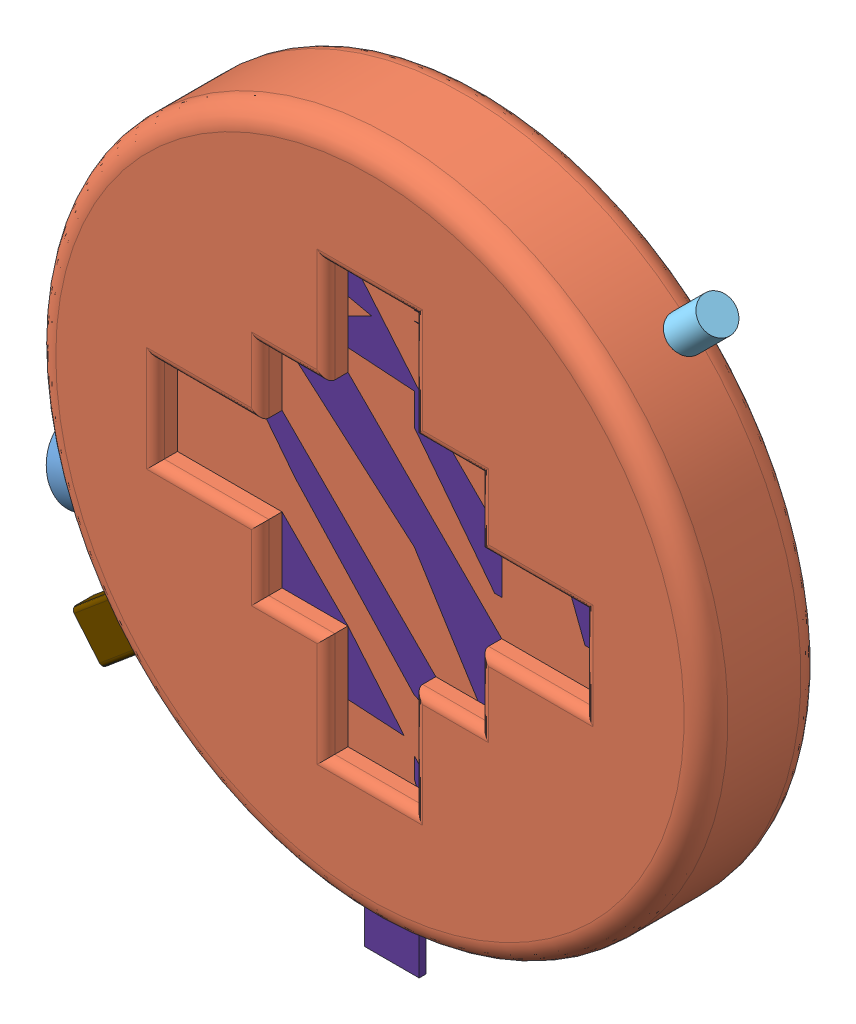
SolidWorks assembly Semafor_s_obalem, configuration Výchozí. Lengths in mm.
Overall size (155.23 162.78 26.6).
173 component instances, 20 part files, 3 mates.
Components (placement in the parent):
- Semafor_kompletni-1: Semafor_kompletni [Výchozí] at origin size (153.13 160.68 23.55)
  - Semafor-1: Semafor [Výchozí] at origin size (148.79 160.68 22.8)
    - Semafor.step-1: Semafor.step [Výchozí] at origin size (148.79 160.68 22.8)
      - LED_WS2812B_PLCC4_5.0x5.0mm_P3.2mm.step-1: LED_WS2812B_PLCC4_5.0x5.0mm_P3.2mm.step [Výchozí] at (-39.4282 65.1 1.65) x (0.5 0.866025 0) z (0 0 1) size (5.4 5 1.6)
        - SOLID.step-1: SOLID.step [Výchozí] at origin size (5.4 5 1.6)
      - LED_WS2812B_PLCC4_5.0x5.0mm_P3.2mm.step-2: LED_WS2812B_PLCC4_5.0x5.0mm_P3.2mm.step [Výchozí] at (-30.05 100.1 1.65) x (0 1 0) z (0 0 1) size (5.4 5 1.6)
        - SOLID.step-1: SOLID.step [Výchozí] at origin size (5.4 5 1.6)
      - LED_WS2812B_PLCC4_5.0x5.0mm_P3.2mm.step-3: LED_WS2812B_PLCC4_5.0x5.0mm_P3.2mm.step [Výchozí] at (-170.05 100.1 1.65) x (0 -1 0) z (0 0 1) size (5.4 5 1.6)
        - SOLID.step-1: SOLID.step [Výchozí] at origin size (5.4 5 1.6)
      - C_0603_1608Metric.step-1: C_0603_1608Metric.step [Výchozí] at (-101.75 33.8 1.65) size (1.6 0.8 0.8)
        - SOLID-0.step-1: SOLID-0.step [Výchozí] at origin size (1.6 0.8 0.8)
      - C_0603_1608Metric.step-2: C_0603_1608Metric.step [Výchozí] at (-43.5875 65.6288 1.65) x (0.5 0.866025 0) z (0 0 1) size (1.6 0.8 0.8)
        - SOLID-0.step-1: SOLID-0.step [Výchozí] at origin size (1.6 0.8 0.8)
      - C_0603_1608Metric.step-3: C_0603_1608Metric.step [Výchozí] at (-134.4288 43.6125 1.65) x (0.866025 -0.5 0) z (0 0 1) size (1.6 0.8 0.8)
        - SOLID-0.step-1: SOLID-0.step [Výchozí] at origin size (1.6 0.8 0.8)
      - C_0603_1608Metric.step-4: C_0603_1608Metric.step [Výchozí] at (-166.15 101.75 1.65) x (0 -1 0) z (0 0 1) size (1.6 0.8 0.8)
        - SOLID-0.step-1: SOLID-0.step [Výchozí] at origin size (1.6 0.8 0.8)
      - LED_WS2812B_PLCC4_5.0x5.0mm_P3.2mm.step-4: LED_WS2812B_PLCC4_5.0x5.0mm_P3.2mm.step [Výchozí] at (-100.05 30.1 1.65) size (5.4 5 1.6)
        - SOLID.step-1: SOLID.step [Výchozí] at origin size (5.4 5 1.6)
      - C_0603_1608Metric.step-5: C_0603_1608Metric.step [Výchozí] at (-158.05 68.5 1.65) x (0.5 -0.866025 0) z (0 0 1) size (1.6 0.8 0.8)
        - SOLID-0.step-1: SOLID-0.step [Výchozí] at origin size (1.6 0.8 0.8)
      - C_0603_1608Metric.step-6: C_0603_1608Metric.step [Výchozí] at (-68.35 41.95 1.65) x (0.866025 0.5 0) z (0 0 1) size (1.6 0.8 0.8)
        - SOLID-0.step-1: SOLID-0.step [Výchozí] at origin size (1.6 0.8 0.8)
      - LED_WS2812B_PLCC4_5.0x5.0mm_P3.2mm.step-5: LED_WS2812B_PLCC4_5.0x5.0mm_P3.2mm.step [Výchozí] at (-100.05 170.1 1.65) x (-1 0 0) z (0 0 1) size (5.4 5 1.6)
        - SOLID.step-1: SOLID.step [Výchozí] at origin size (5.4 5 1.6)
      - LED_WS2812B_PLCC4_5.0x5.0mm_P3.2mm.step-6: LED_WS2812B_PLCC4_5.0x5.0mm_P3.2mm.step [Výchozí] at (-39.4282 135.1 1.65) x (-0.5 0.866025 0) z (0 0 1) size (5.4 5 1.6)
        - SOLID.step-1: SOLID.step [Výchozí] at origin size (5.4 5 1.6)
      - LED_WS2812B_PLCC4_5.0x5.0mm_P3.2mm.step-7: LED_WS2812B_PLCC4_5.0x5.0mm_P3.2mm.step [Výchozí] at (-160.6718 65.1 1.65) x (0.5 -0.866025 0) z (0 0 1) size (5.4 5 1.6)
        - SOLID.step-1: SOLID.step [Výchozí] at origin size (5.4 5 1.6)
      - LED_WS2812B_PLCC4_5.0x5.0mm_P3.2mm.step-8: LED_WS2812B_PLCC4_5.0x5.0mm_P3.2mm.step [Výchozí] at (-65.05 39.4782 1.65) x (0.866025 0.5 0) z (0 0 1) size (5.4 5 1.6)
        - SOLID.step-1: SOLID.step [Výchozí] at origin size (5.4 5 1.6)
      - C_0603_1608Metric.step-7: C_0603_1608Metric.step [Výchozí] at (-65.45 156.55 1.65) x (-0.866025 0.5 0) z (0 0 1) size (1.6 0.8 0.8)
        - SOLID-0.step-1: SOLID-0.step [Výchozí] at origin size (1.6 0.8 0.8)
      - C_0603_1608Metric.step-8: C_0603_1608Metric.step [Výchozí] at (-33.9 98.45 1.65) x (0 1 0) z (0 0 1) size (1.6 0.8 0.8)
        - SOLID-0.step-1: SOLID-0.step [Výchozí] at origin size (1.6 0.8 0.8)
      - C_0603_1608Metric.step-9: C_0603_1608Metric.step [Výchozí] at (-98.4 166.3 1.65) x (-1 0 0) z (0 0 1) size (1.6 0.8 0.8)
        - SOLID-0.step-1: SOLID-0.step [Výchozí] at origin size (1.6 0.8 0.8)
      - LED_WS2812B_PLCC4_5.0x5.0mm_P3.2mm.step-9: LED_WS2812B_PLCC4_5.0x5.0mm_P3.2mm.step [Výchozí] at (-160.6718 135.1 1.65) x (-0.5 -0.866025 0) z (0 0 1) size (5.4 5 1.6)
        - SOLID.step-1: SOLID.step [Výchozí] at origin size (5.4 5 1.6)
      - LED_WS2812B_PLCC4_5.0x5.0mm_P3.2mm.step-10: LED_WS2812B_PLCC4_5.0x5.0mm_P3.2mm.step [Výchozí] at (-65.05 160.7218 1.65) x (-0.866025 0.5 0) z (0 0 1) size (5.4 5 1.6)
        - SOLID.step-1: SOLID.step [Výchozí] at origin size (5.4 5 1.6)
      - C_0603_1608Metric.step-10: C_0603_1608Metric.step [Výchozí] at (-156.35 134.6 1.65) x (-0.5 -0.866025 0) z (0 0 1) size (1.6 0.8 0.8)
        - SOLID-0.step-1: SOLID-0.step [Výchozí] at origin size (1.6 0.8 0.8)
      - LED_WS2812B_PLCC4_5.0x5.0mm_P3.2mm.step-11: LED_WS2812B_PLCC4_5.0x5.0mm_P3.2mm.step [Výchozí] at (-135.05 160.7218 1.65) x (-0.866025 -0.5 0) z (0 0 1) size (5.4 5 1.6)
        - SOLID.step-1: SOLID.step [Výchozí] at origin size (5.4 5 1.6)
      - C_0603_1608Metric.step-11: C_0603_1608Metric.step [Výchozí] at (-131.65 158.3 1.65) x (-0.866025 -0.5 0) z (0 0 1) size (1.6 0.8 0.8)
        - SOLID-0.step-1: SOLID-0.step [Výchozí] at origin size (1.6 0.8 0.8)
      - C_0603_1608Metric.step-12: C_0603_1608Metric.step [Výchozí] at (-42.05 131.8 1.65) x (-0.5 0.866025 0) z (0 0 1) size (1.6 0.8 0.8)
        - SOLID-0.step-1: SOLID-0.step [Výchozí] at origin size (1.6 0.8 0.8)
      - LED_WS2812B_PLCC4_5.0x5.0mm_P3.2mm.step-12: LED_WS2812B_PLCC4_5.0x5.0mm_P3.2mm.step [Výchozí] at (-135.05 39.4782 1.65) x (0.866025 -0.5 0) z (0 0 1) size (5.4 5 1.6)
        - SOLID.step-1: SOLID.step [Výchozí] at origin size (5.4 5 1.6)
      - R_0603_1608Metric.step-1: R_0603_1608Metric.step [Výchozí] at (-119.75 147.925 -0.05) x (0 -1 0) z (0 0 -1) size (1.6 0.8 0.45)
        - SOLID-1.step-1: SOLID-1.step [Výchozí] at origin size (1.6 0.8 0.45)
      - R_0603_1608Metric.step-2: R_0603_1608Metric.step [Výchozí] at (-115.95 147.9 -0.05) x (0 -1 0) z (0 0 -1) size (1.6 0.8 0.45)
        - SOLID-1.step-1: SOLID-1.step [Výchozí] at origin size (1.6 0.8 0.45)
      - D_SOD-123.step-1: D_SOD-123.step [Výchozí] at (-130.0125 82.075 -0.05) x (-1 0 0) z (0 0 -1) size (3.8 1.6 1.25)
        - SOLID-2.step-1: SOLID-2.step [Výchozí] at origin size (3.8 1.6 1.25)
      - E22_900T22D.step-1: E22_900T22D.step [Výchozí] at (-60.45 137.7711 -0.05) x (-0.707107 -0.707107 0) z (0 0 -1) size (50 21 17.3)
        - SOLID-3.step-1: SOLID-3.step [Výchozí] at origin size (50 21 17.3)
      - D_SOD-123.step-2: D_SOD-123.step [Výchozí] at (-96.1 29.05 -0.05) x (0 -1 0) z (0 0 -1) size (3.8 1.6 1.25)
        - SOLID-2.step-1: SOLID-2.step [Výchozí] at origin size (3.8 1.6 1.25)
      - PinSocket_1x03_P2.54mm_Vertical.step-1: PinSocket_1x03_P2.54mm_Vertical.step [Výchozí] at (-143.675 75.375 -0.05) x (0 1 0) z (0 0 -1) size (2.54 7.62 10.1)
        - SOLID-4.step-1: SOLID-4.step [Výchozí] at origin size (2.54 7.62 10.1)
      - D_SOD-323.step-1: D_SOD-323.step [Výchozí] at (-142.6 58.8 -0.05) x (0.642788 -0.766044 0) z (0 0 -1) size (2.5 1.25 1.1)
        - SOLID-5.step-1: SOLID-5.step [Výchozí] at origin size (2.5 1.25 1.1)
      - C_0603_1608Metric.step-13: C_0603_1608Metric.step [Výchozí] at (-158.9591 131.0993 -0.05) x (-0.939693 0.34202 0) z (0 0 -1) size (1.6 0.8 0.8)
        - SOLID-0.step-1: SOLID-0.step [Výchozí] at origin size (1.6 0.8 0.8)
      - R_0603_1608Metric.step-3: R_0603_1608Metric.step [Výchozí] at (-83.3756 132.275 -0.05) x (-1 0 0) z (0 0 -1) size (1.6 0.8 0.45)
        - SOLID-1.step-1: SOLID-1.step [Výchozí] at origin size (1.6 0.8 0.45)
      - R_0603_1608Metric.step-4: R_0603_1608Metric.step [Výchozí] at (-118.05 147.9 -0.05) x (0 -1 0) z (0 0 -1) size (1.6 0.8 0.45)
        - SOLID-1.step-1: SOLID-1.step [Výchozí] at origin size (1.6 0.8 0.45)
      - R_0603_1608Metric.step-5: R_0603_1608Metric.step [Výchozí] at (-116.95 136.3 -0.05) x (0 -1 0) z (0 0 -1) size (1.6 0.8 0.45)
        - SOLID-1.step-1: SOLID-1.step [Výchozí] at origin size (1.6 0.8 0.45)
      - C_0805_2012Metric.step-1: C_0805_2012Metric.step [Výchozí] at (-152.9591 126.5493 -0.05) x (0.939693 -0.34202 0) z (0 0 -1) size (2 1.25 1.25)
        - SOLID-6.step-1: SOLID-6.step [Výchozí] at origin size (2 1.25 1.25)
      - LED_0603_1608Metric.step-1: LED_0603_1608Metric.step [Výchozí] at (-147.525 84.025 -0.05) x (-1 0 0) z (0 0 -1) size (1.6 0.8 1.1)
        - SOLID-7.step-1: SOLID-7.step [Výchozí] at origin size (1.6 0.8 1.1)
      - SOT-23.step-1: SOT-23.step [Výchozí] at (-83.3256 136.55 -0.05) x (0 1 0) z (0 0 -1) size (2.5 3 1.2)
        - SOLID-8.step-1: SOLID-8.step [Výchozí] at origin size (2.5 3 1.2)
      - SOT-23.step-2: SOT-23.step [Výchozí] at (-146.9091 122.0993 -0.05) x (0.939693 -0.34202 0) z (0 0 -1) size (2.5 3 1.2)
        - SOLID-8.step-1: SOLID-8.step [Výchozí] at origin size (2.5 3 1.2)
      - R_0603_1608Metric.step-6: R_0603_1608Metric.step [Výchozí] at (-120.725 43.975 -0.05) x (-1 0 0) z (0 0 -1) size (1.6 0.8 0.45)
        - SOLID-1.step-1: SOLID-1.step [Výchozí] at origin size (1.6 0.8 0.45)
      - C_0805_2012Metric.step-2: C_0805_2012Metric.step [Výchozí] at (-159.7591 129.0993 -0.05) x (-0.939693 0.34202 0) z (0 0 -1) size (2 1.25 1.25)
        - SOLID-6.step-1: SOLID-6.step [Výchozí] at origin size (2 1.25 1.25)
      - R_0603_1608Metric.step-7: R_0603_1608Metric.step [Výchozí] at (-120.15 136.3 -0.05) x (0 -1 0) z (0 0 -1) size (1.6 0.8 0.45)
        - SOLID-1.step-1: SOLID-1.step [Výchozí] at origin size (1.6 0.8 0.45)
      - D_SOD-323.step-2: D_SOD-323.step [Výchozí] at (-147.5 62.875 -0.05) x (-0.766044 -0.642788 0) z (0 0 -1) size (2.5 1.25 1.1)
        - SOLID-5.step-1: SOLID-5.step [Výchozí] at origin size (2.5 1.25 1.1)
      - C_0805_2012Metric.step-3: C_0805_2012Metric.step [Výchozí] at (-128.3875 78.75 -0.05) x (0 -1 0) z (0 0 -1) size (2 1.25 1.25)
        - SOLID-6.step-1: SOLID-6.step [Výchozí] at origin size (2 1.25 1.25)
      - R_0603_1608Metric.step-8: R_0603_1608Metric.step [Výchozí] at (-143.0091 117.4493 -0.05) x (0.939693 -0.34202 0) z (0 0 -1) size (1.6 0.8 0.45)
        - SOLID-1.step-1: SOLID-1.step [Výchozí] at origin size (1.6 0.8 0.45)
      - LED_0603_1608Metric.step-2: LED_0603_1608Metric.step [Výchozí] at (-109.425 43.2125 -0.05) x (0 -1 0) z (0 0 -1) size (1.6 0.8 1.1)
        - SOLID-7.step-1: SOLID-7.step [Výchozí] at origin size (1.6 0.8 1.1)
      - R_0603_1608Metric.step-9: R_0603_1608Metric.step [Výchozí] at (-135.1875 77.025 -0.05) x (0 1 0) z (0 0 -1) size (1.6 0.8 0.45)
        - SOLID-1.step-1: SOLID-1.step [Výchozí] at origin size (1.6 0.8 0.45)
      - USB_C.step-1: USB_C.step [Výchozí] at (-154.7 55.1 -0.05) x (-0.766044 -0.642788 0) z (0 0 -1) size (7.5 9 3.5)
        - SOLID-9.step-1: SOLID-9.step [Výchozí] at origin size (7.5 9 3.5)
      - Battery_pack.step-1: Battery_pack.step [Výchozí] at (-99.9 62.1 -0.05) x (-1 0 0) z (0 0 -1) size (77 21 19.5)
        - SOLID-10.step-1: SOLID-10.step [Výchozí] at origin size (77 21 19.5)
      - LED_0603_1608Metric.step-3: LED_0603_1608Metric.step [Výchozí] at (-107.575 43.225 -0.05) x (0 -1 0) z (0 0 -1) size (1.6 0.8 1.1)
        - SOLID-7.step-1: SOLID-7.step [Výchozí] at origin size (1.6 0.8 1.1)
      - R_0603_1608Metric.step-10: R_0603_1608Metric.step [Výchozí] at (-144.1125 87.05 -0.05) x (1 0 0) z (0 0 -1) size (1.6 0.8 0.45)
        - SOLID-1.step-1: SOLID-1.step [Výchozí] at origin size (1.6 0.8 0.45)
      - D_SOD-123.step-3: D_SOD-123.step [Výchozí] at (-117.975 155.17 -0.05) x (-1 0 0) z (0 0 -1) size (3.8 1.6 1.25)
        - SOLID-2.step-1: SOLID-2.step [Výchozí] at origin size (3.8 1.6 1.25)
      - R_0603_1608Metric.step-11: R_0603_1608Metric.step [Výchozí] at (-114.175 160.345 -0.05) x (0 -1 0) z (0 0 -1) size (1.6 0.8 0.45)
        - SOLID-1.step-1: SOLID-1.step [Výchozí] at origin size (1.6 0.8 0.45)
      - R_0603_1608Metric.step-12: R_0603_1608Metric.step [Výchozí] at (-150.9091 118.3743 -0.05) x (-0.34202 -0.939693 0) z (0 0 -1) size (1.6 0.8 0.45)
        - SOLID-1.step-1: SOLID-1.step [Výchozí] at origin size (1.6 0.8 0.45)
      - D_SOD-323.step-3: D_SOD-323.step [Výchozí] at (-98.4 29.65 -0.05) x (0 1 0) z (0 0 -1) size (2.5 1.25 1.1)
        - SOLID-5.step-1: SOLID-5.step [Výchozí] at origin size (2.5 1.25 1.1)
      - SOIC-14_3.9x8.7mm_P1.27mm.step-1: SOIC-14_3.9x8.7mm_P1.27mm.step [Výchozí] at (-118.5 142.1 -0.05) x (0 -1 0) z (0 0 -1) size (6 8.7 1.75)
        - SOLID-11.step-1: SOLID-11.step [Výchozí] at origin size (6 8.7 1.75)
      - C_0603_1608Metric.step-14: C_0603_1608Metric.step [Výchozí] at (-124.55 142.3493 -0.05) x (0 -1 0) z (0 0 -1) size (1.6 0.8 0.8)
        - SOLID-0.step-1: SOLID-0.step [Výchozí] at origin size (1.6 0.8 0.8)
      - R_0603_1608Metric.step-13: R_0603_1608Metric.step [Výchozí] at (-147.4841 125.4493 -0.05) x (0.939693 -0.34202 0) z (0 0 -1) size (1.6 0.8 0.45)
        - SOLID-1.step-1: SOLID-1.step [Výchozí] at origin size (1.6 0.8 0.45)
      - C_0805_2012Metric.step-4: C_0805_2012Metric.step [Výchozí] at (-126.5 142.3993 -0.05) x (0 -1 0) z (0 0 -1) size (2 1.25 1.25)
        - SOLID-6.step-1: SOLID-6.step [Výchozí] at origin size (2 1.25 1.25)
      - R_0603_1608Metric.step-14: R_0603_1608Metric.step [Výchozí] at (-139.1625 81.2 -0.05) x (0 -1 0) z (0 0 -1) size (1.6 0.8 0.45)
        - SOLID-1.step-1: SOLID-1.step [Výchozí] at origin size (1.6 0.8 0.45)
      - R_0603_1608Metric.step-15: R_0603_1608Metric.step [Výchozí] at (-132.6875 77.875 -0.05) x (1 0 0) z (0 0 -1) size (1.6 0.8 0.45)
        - SOLID-1.step-1: SOLID-1.step [Výchozí] at origin size (1.6 0.8 0.45)
      - SOT-23.step-3: SOT-23.step [Výchozí] at (-118.675 160.445 -0.05) x (-1 0 0) z (0 0 -1) size (2.5 3 1.2)
        - SOLID-8.step-1: SOLID-8.step [Výchozí] at origin size (2.5 3 1.2)
      - R_0402_1005Metric.step-1: R_0402_1005Metric.step [Výchozí] at (-150.45 61 -0.05) x (0.766044 0.642788 0) z (0 0 -1) size (1 0.5 0.35)
        - SOLID-12.step-1: SOLID-12.step [Výchozí] at origin size (1 0.5 0.35)
      - C_0805_2012Metric.step-5: C_0805_2012Metric.step [Výchozí] at (-114.675 48.525 -0.05) x (-1 0 0) z (0 0 -1) size (2 1.25 1.25)
        - SOLID-6.step-1: SOLID-6.step [Výchozí] at origin size (2 1.25 1.25)
      - R_0603_1608Metric.step-16: R_0603_1608Metric.step [Výchozí] at (-152.1341 114.7493 -0.05) x (-0.34202 -0.939693 0) z (0 0 -1) size (1.6 0.8 0.45)
        - SOLID-1.step-1: SOLID-1.step [Výchozí] at origin size (1.6 0.8 0.45)
      - C_0603_1608Metric.step-15: C_0603_1608Metric.step [Výchozí] at (-78.4756 143.175 -0.05) x (0 -1 0) z (0 0 -1) size (1.6 0.8 0.8)
        - SOLID-0.step-1: SOLID-0.step [Výchozí] at origin size (1.6 0.8 0.8)
      - C_0805_2012Metric.step-6: C_0805_2012Metric.step [Výchozí] at (-120.625 46.525 -0.05) x (-1 0 0) z (0 0 -1) size (2 1.25 1.25)
        - SOLID-6.step-1: SOLID-6.step [Výchozí] at origin size (2 1.25 1.25)
      - R_0603_1608Metric.step-17: R_0603_1608Metric.step [Výchozí] at (-115.3 136.3 -0.05) x (0 1 0) z (0 0 -1) size (1.6 0.8 0.45)
        - SOLID-1.step-1: SOLID-1.step [Výchozí] at origin size (1.6 0.8 0.45)
      - SOT-23-5.step-1: SOT-23-5.step [Výchozí] at (-135.2875 81.1 -0.05) x (-1 0 0) z (0 0 -1) size (2.8 2.9 1.55)
        - SOLID-13.step-1: SOLID-13.step [Výchozí] at origin size (2.8 2.9 1.55)
      - R_0402_1005Metric.step-2: R_0402_1005Metric.step [Výchozí] at (-148.35 58.75 -0.05) x (0.766044 0.642788 0) z (0 0 -1) size (1 0.5 0.35)
        - SOLID-12.step-1: SOLID-12.step [Výchozí] at origin size (1 0.5 0.35)
      - C_0805_2012Metric.step-7: C_0805_2012Metric.step [Výchozí] at (-136.7875 84.075 -0.05) x (1 0 0) z (0 0 -1) size (2 1.25 1.25)
        - SOLID-6.step-1: SOLID-6.step [Výchozí] at origin size (2 1.25 1.25)
      - PinHeader_1x02_P2.54mm_Vertical.step-1: PinHeader_1x02_P2.54mm_Vertical.step [Výchozí] at (-83.2244 144.25 -0.05) x (-1 0 0) z (0 0 -1) size (2.54 5.08 11.54)
        - SOLID-14.step-1: SOLID-14.step [Výchozí] at origin size (2.54 5.08 11.54)
      - D_SOD-323.step-4: D_SOD-323.step [Výchozí] at (-146.2 61.275 -0.05) x (-0.766044 -0.642788 0) z (0 0 -1) size (2.5 1.25 1.1)
        - SOLID-5.step-1: SOLID-5.step [Výchozí] at origin size (2.5 1.25 1.1)
      - LED_0603_1608Metric.step-4: LED_0603_1608Metric.step [Výchozí] at (-147.5125 87.075 -0.05) x (-1 0 0) z (0 0 -1) size (1.6 0.8 1.1)
        - SOLID-7.step-1: SOLID-7.step [Výchozí] at origin size (1.6 0.8 1.1)
      - R_0603_1608Metric.step-18: R_0603_1608Metric.step [Výchozí] at (-156.1591 128.8493 -0.05) x (0.939693 -0.34202 0) z (0 0 -1) size (1.6 0.8 0.45)
        - SOLID-1.step-1: SOLID-1.step [Výchozí] at origin size (1.6 0.8 0.45)
      - R_0603_1608Metric.step-19: R_0603_1608Metric.step [Výchozí] at (-144.15 84.05 -0.05) x (1 0 0) z (0 0 -1) size (1.6 0.8 0.45)
        - SOLID-1.step-1: SOLID-1.step [Výchozí] at origin size (1.6 0.8 0.45)
      - R_0603_1608Metric.step-20: R_0603_1608Metric.step [Výchozí] at (-110.275 40.775 -0.05) x (1 0 0) z (0 0 -1) size (1.6 0.8 0.45)
        - SOLID-1.step-1: SOLID-1.step [Výchozí] at origin size (1.6 0.8 0.45)
      - D_SOD-123.step-4: D_SOD-123.step [Výchozí] at (-144.6 55.65 -0.05) x (-0.766044 -0.642788 0) z (0 0 -1) size (3.8 1.6 1.25)
        - SOLID-2.step-1: SOLID-2.step [Výchozí] at origin size (3.8 1.6 1.25)
      - SOT-23.step-4: SOT-23.step [Výchozí] at (-143.8591 114.7993 -0.05) x (0.939693 -0.34202 0) z (0 0 -1) size (2.5 3 1.2)
        - SOLID-8.step-1: SOLID-8.step [Výchozí] at origin size (2.5 3 1.2)
      - R_0603_1608Metric.step-21: R_0603_1608Metric.step [Výchozí] at (-155.1091 131.9243 -0.05) x (-0.34202 -0.939693 0) z (0 0 -1) size (1.6 0.8 0.45)
        - SOLID-1.step-1: SOLID-1.step [Výchozí] at origin size (1.6 0.8 0.45)
      - R_0603_1608Metric.step-22: R_0603_1608Metric.step [Výchozí] at (-118.55 136.3 -0.05) x (0 -1 0) z (0 0 -1) size (1.6 0.8 0.45)
        - SOLID-1.step-1: SOLID-1.step [Výchozí] at origin size (1.6 0.8 0.45)
      - R_0603_1608Metric.step-23: R_0603_1608Metric.step [Výchozí] at (-121.75 136.2993 -0.05) x (0 -1 0) z (0 0 -1) size (1.6 0.8 0.45)
        - SOLID-1.step-1: SOLID-1.step [Výchozí] at origin size (1.6 0.8 0.45)
      - D_SOD-123.step-5: D_SOD-123.step [Výchozí] at (-74.5506 143.175 -0.05) x (0 -1 0) z (0 0 -1) size (3.8 1.6 1.25)
        - SOLID-2.step-1: SOLID-2.step [Výchozí] at origin size (3.8 1.6 1.25)
      - Semafor PCB.step-1: Semafor PCB.step [Výchozí] at origin size (148.79 160.68 1.6)
  - USB_cable-1: USB_cable [Výchozí] at (-163.701 47.5472 -4.8) x (0.766044 0.642788 0) z (0 0 1) size (20 11 6)
  - Button-2: Button [Výchozí] at (-162.6501 76.4818 -4.5) x (-0.347544 0.937664 0) z (0 0 1) size (17 22 17)
- Obal-1: Obal [Výchozí] at (-100 99.9315 0) x (-1 0 0) z (0 0 -1) size (153 153 26.6)
Mates (geometry in assembly coordinates):
- Sjednocená1: coincident: plane of Semafor_kompletni-1/Semafor-1/Semafor.step-1/Semafor PCB.step-1 through (-100.0019 93.8452 1.6) normal (0 0 1); plane of Obal-1 through (-100 99.9315 1.6) normal (0 0 1)
- Rovnoběžná1: parallel: plane of Semafor_kompletni-1/Semafor-1/Semafor.step-1/Semafor PCB.step-1 through (-93.8 13.65 0) normal (0 -1 0); plane of Obal-1 through (-110 51.1315 1.6) normal (0 1 0)
- Soustředná1: concentric anti-aligned: circle of Semafor_kompletni-1/Semafor-1/Semafor.step-1/Semafor PCB.step-1; circle of Obal-1
